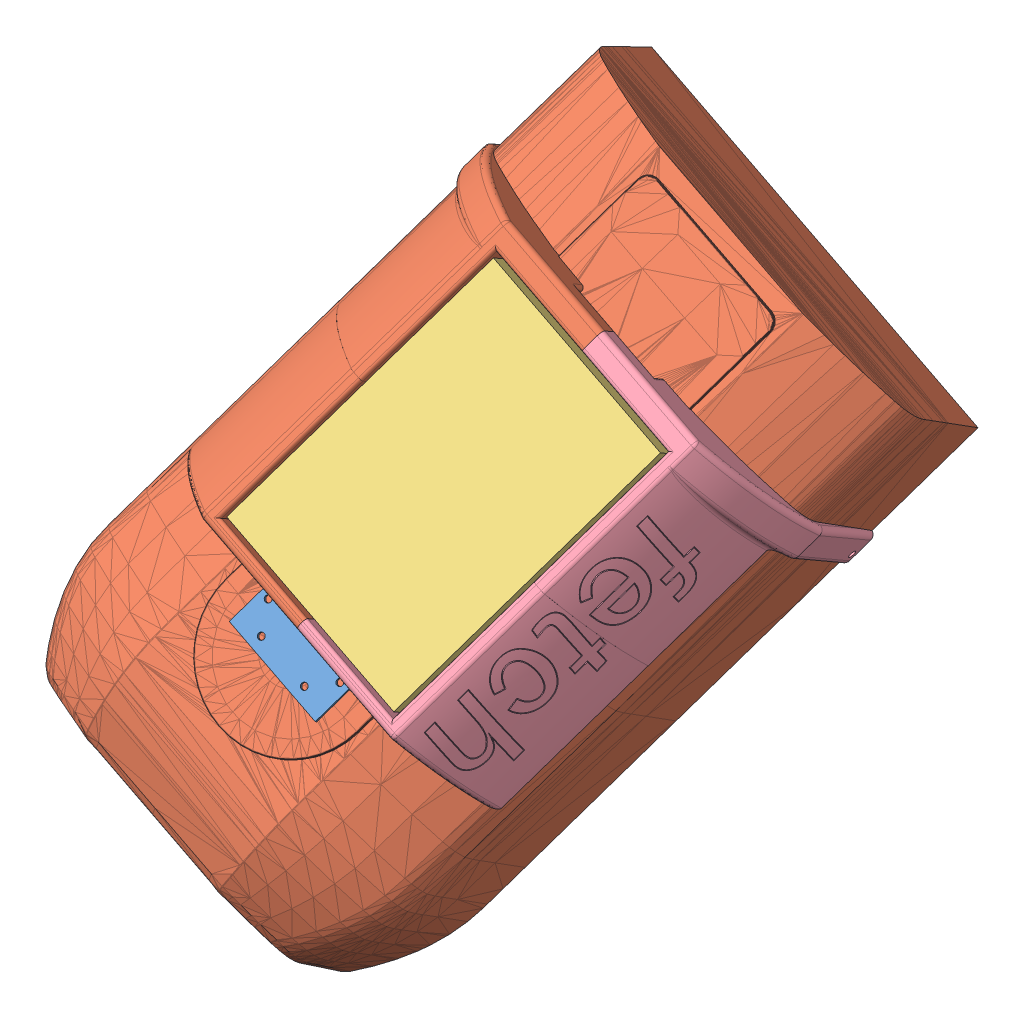
SolidWorks assembly monitor_fixture, configuration ﾃﾞﾌｫﾙﾄ. Lengths in mm.
Overall size (576.71 666.61 524.87).
4 component instances, 4 part files, 12 mates.
Components (placement in the parent):
- monitor_fixture_center-1: monitor_fixture_center [ﾃﾞﾌｫﾙﾄ] at (-548.9826 -167.4749 899.101) x (0.890746 -0.454501 0) z (-0.289367 -0.567112 -0.771136) size (176 240 5)
- monitor_fixture_right-1: monitor_fixture_right [ﾃﾞﾌｫﾙﾄ] at (-449.6972 27.108 474.9476) x (-0.289367 -0.567112 -0.771136) z (-0.350482 -0.686887 0.63667) size (206.32 354.37 574.5)
- monitor-1: monitor [ﾃﾞﾌｫﾙﾄ] at (-482.1989 -36.5899 825.7658) x (-0.350482 -0.686887 0.63667) z (-0.289367 -0.567112 -0.771136) size (252 183.51 35)
- monitor_fixture_left-3: monitor_fixture_left [ﾃﾞﾌｫﾙﾄ] at (-449.6972 27.108 474.9476) x (-0.289367 -0.567112 -0.771136) z (-0.350482 -0.686887 0.63667) size (206.06 183.53 313.72)
Mates (geometry in assembly coordinates):
- 同心円10: concentric anti-aligned: circle of monitor_fixture_center-1; circle of monitor_fixture_right-1
- 同心円11: concentric anti-aligned: circle of monitor_fixture_center-1; circle of monitor_fixture_right-1
- 同心円12: concentric aligned: circle of monitor_fixture_center-1; circle of monitor-1
- 同心円13: concentric aligned: circle of monitor_fixture_center-1; circle of monitor-1
- 同心円14: concentric anti-aligned: circle of monitor_fixture_center-1; circle of monitor_fixture_right-1
- 同心円15: concentric anti-aligned: circle of monitor_fixture_center-1; circle of monitor_fixture_right-1
- 一致6: coincident anti-aligned: plane of monitor_fixture_center-1 through (-548.4038 -166.3407 900.6433) normal (0.289367 0.567112 0.771136); plane of monitor_fixture_right-1 through (-581.1105 -54.423 830.6096) normal (-0.289367 -0.567112 -0.771136)
- 一致9: coincident anti-aligned: plane of monitor_fixture_center-1 through (-548.4038 -166.3407 900.6433) normal (0.289367 0.567112 0.771136); plane of monitor-1 through (-492.3267 -56.4388 798.7761) normal (-0.289367 -0.567112 -0.771136)
- 一致10: coincident anti-aligned: plane of monitor_fixture_right-1 through (-590.9695 -249.7624 755.7962) normal (0.890746 -0.454501 0); plane of monitor_fixture_left-3 through (-590.9695 -249.7624 755.7962) normal (-0.890746 0.454501 0)
- 一致11: coincident aligned: plane of monitor_fixture_right-1 through (-590.9695 -249.7624 755.7962) normal (-0.350482 -0.686887 0.63667); plane of monitor_fixture_left-3 through (-590.9695 -249.7624 755.7962) normal (-0.350482 -0.686887 0.63667)
- 一致12: coincident aligned: plane of monitor_fixture_right-1 through (-384.5897 154.7081 648.4532) normal (0.289367 0.567112 0.771136); plane of monitor_fixture_left-3 through (-384.5897 154.7081 648.4532) normal (0.289367 0.567112 0.771136)
- 同心円16: concentric anti-aligned: circle of monitor_fixture_center-1; circle of monitor_fixture_left-3
